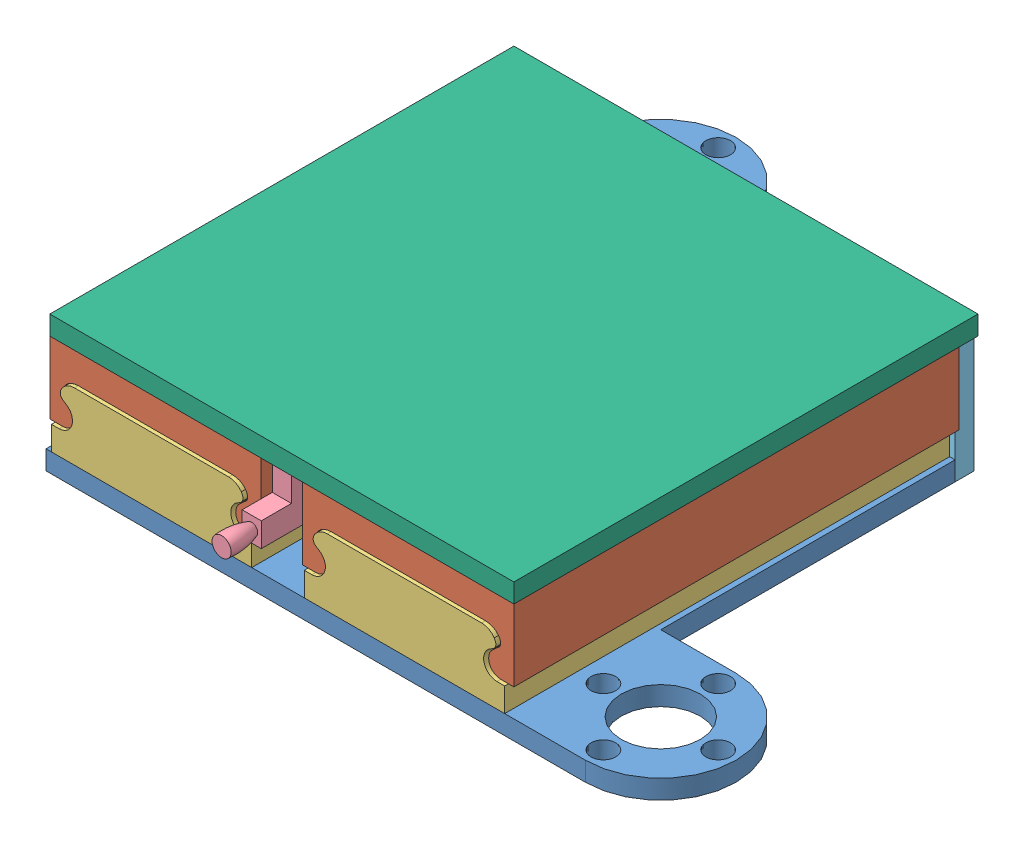
SolidWorks assembly Elevator Assembly, configuration Default. Lengths in mm.
Overall size (102 22.22 111.38).
8 component instances, 6 part files, 22 mates.
Components (placement in the parent):
- Elevator Platform-1: Elevator Platform [Default] at (42.3916 56.1213 78.8759) size (102 3.17 102)
- Slider Outside Piece-1: Slider Outside Piece [Default] at (21.4104 75.1713 116.7454) x (0 0 -1) z (-1 0 0) size (73.82 11.91 35.04)
- Slider Outside Piece-2: Slider Outside Piece [Default] at (63.3729 75.1713 116.7454) x (0 0 -1) z (-1 0 0) size (73.82 11.91 35.04)
- Slider Inside Piece-1: Slider Inside Piece [Default] at (21.4104 75.1713 117.3759) x (0 0 -1) z (-1 0 0) size (73.82 11.11 33.23)
- Slider Inside Piece-2: Slider Inside Piece [Default] at (63.3729 75.1713 117.3759) x (0 0 -1) z (-1 0 0) size (73.82 11.11 33.23)
- Pulling Knob-1: Pulling Knob [Default] at (41.6081 73.0235 116.7454) size (3.45 8 20.01)
- Back Wall-1: Back Wall [Default] at (3.8916 59.2963 41.3989) size (77 19.05 3.18)
- Elevator Slide-3: Elevator Slide [Default] at (42.3916 75.1713 78.2454) size (77 3.17 77)
Mates (geometry in assembly coordinates):
- Parallel1: parallel anti-aligned: plane of Slider Outside Piece-1 through (21.4104 70.4088 42.9204) normal (0 -1 0); plane of Slider Inside Piece-1 through (21.4104 70.4088 43.5509) normal (0 1 0)
- Parallel2: parallel aligned: plane of Slider Outside Piece-1 through (21.4104 75.1713 116.7454) normal (0 0 1); plane of Slider Inside Piece-1 through (21.4104 75.1713 117.3759) normal (0 0 1)
- Parallel3: parallel anti-aligned: plane of Slider Outside Piece-1 through (21.4104 63.265 42.9204) normal (0 -1 0); plane of Slider Inside Piece-1 through (21.4104 63.265 43.5509) normal (0 1 0)
- Coincident16: coincident anti-aligned: plane of Slider Outside Piece-1 through (21.4104 70.4088 42.9204) normal (0 -1 0); plane of Slider Inside Piece-1 through (21.4104 70.4088 43.5509) normal (0 1 0)
- Coincident17: coincident aligned: line of Slider Outside Piece-1 through (6.0645 63.265 42.9204) axis (0 0 1); line of Slider Inside Piece-1 through (6.0645 63.265 43.5509) axis (0 0 1)
- Parallel4: parallel anti-aligned: plane of Slider Outside Piece-2 through (63.3729 70.4088 42.9204) normal (0 -1 0); plane of Slider Inside Piece-2 through (63.3729 70.4088 43.5509) normal (0 1 0)
- Parallel5: parallel aligned: plane of Slider Outside Piece-2 through (63.3729 75.1713 42.9204) normal (0 0 -1); plane of Slider Inside Piece-2 through (63.3729 75.1713 43.5509) normal (0 0 -1)
- Coincident20: coincident aligned: line of Slider Outside Piece-2 through (78.7187 63.265 42.9204) axis (0 0 1); line of Slider Inside Piece-2 through (78.7187 63.265 43.5509) axis (0 0 1)
- Coincident24: coincident anti-aligned: plane of Elevator Platform-1 through (42.3916 59.2963 78.8759) normal (0 1 0); plane of Slider Inside Piece-1 through (21.4104 59.2963 43.5509) normal (0 -1 0)
- Coincident25: coincident anti-aligned: plane of Elevator Platform-1 through (42.3916 59.2963 78.8759) normal (0 1 0); plane of Slider Inside Piece-2 through (63.3729 59.2963 43.5509) normal (0 -1 0)
- Coincident28: coincident aligned: plane of Elevator Platform-1 through (42.3916 59.2963 117.3759) normal (0 0 1); plane of Slider Inside Piece-1 through (21.4104 75.1713 117.3759) normal (0 0 1)
- Coincident41: coincident anti-aligned: plane of Elevator Platform-1 through (42.3916 59.2963 78.8759) normal (0 1 0); plane of Back Wall-1 through (80.8916 59.2963 43.5509) normal (0 -1 0)
- Coincident42: coincident anti-aligned: line of Elevator Platform-1 through (28.8916 59.2963 40.3759) axis (1 0 0); line of Back Wall-1 through (10.8916 59.2963 40.3759) axis (-1 0 0)
- Coincident44: coincident anti-aligned: line of Elevator Platform-1 through (80.8916 56.1213 43.5509) axis (0 1 0); line of Back Wall-1 through (80.8916 75.1713 43.5509) axis (0 -1 0)
- Coincident45: coincident anti-aligned: plane of Slider Outside Piece-2 through (63.3729 75.1713 42.9204) normal (0 1 0); plane of Elevator Slide-3 through (42.3916 75.1713 78.2454) normal (0 -1 0)
- Coincident46: coincident anti-aligned: plane of Slider Outside Piece-1 through (21.4104 75.1713 42.9204) normal (0 1 0); plane of Elevator Slide-3 through (42.3916 75.1713 78.2454) normal (0 -1 0)
- Coincident47: coincident aligned: line of Slider Outside Piece-1 through (3.8916 75.1713 116.7454) axis (1 0 0); line of Elevator Slide-3 through (3.8916 75.1713 116.7454) axis (1 0 0)
- Coincident48: coincident aligned: line of Slider Outside Piece-2 through (45.8541 75.1713 116.7454) axis (1 0 0); line of Elevator Slide-3 through (3.8916 75.1713 116.7454) axis (1 0 0)
- Coincident49: coincident aligned: line of Slider Outside Piece-2 through (80.8916 75.1713 116.7454) axis (0 0 -1); line of Elevator Slide-3 through (80.8916 75.1713 116.7454) axis (0 0 -1)
- Coincident50: coincident anti-aligned: plane of Pulling Knob-1 through (40.8041 75.1713 106.7454) normal (0 1 0); plane of Elevator Slide-3 through (42.3916 75.1713 78.2454) normal (0 -1 0)
- Coincident51: coincident aligned: plane of Pulling Knob-1 through (41.6081 73.0235 116.7454) normal (0 0 1); plane of Elevator Slide-3 through (3.8916 78.3463 116.7454) normal (0 0 1)
- Coincident52: coincident: point of Pulling Knob-1; unknown of Elevator Slide-3
